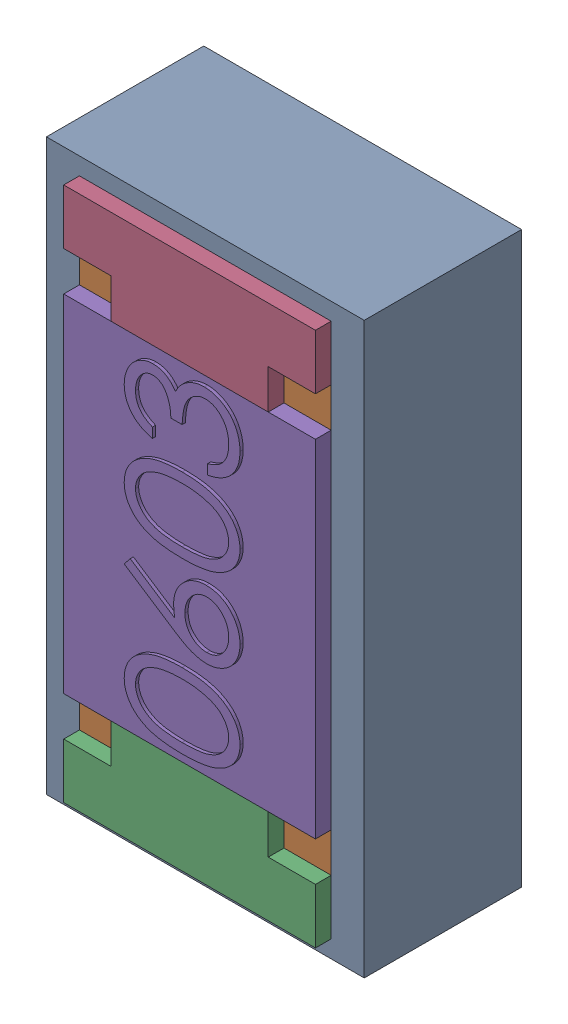
SolidWorks assembly SB5, configuration Default. Lengths in mm.
Overall size (1.01 1.81 0.56).
3 component instances, 2 part files, 0 mates.
Components (placement in the parent):
- 1088884704-1: 1088884704 [Default] at (13.8 21.425 0) size (1.01 1.81 0.5)
  - Extruded-0-1: Extruded-0 [Default] at origin size (1.01 1.81 0.5)
- R0603-1: R0603 [Default] at (13.7999 21.4251 0) x (0 1 0) z (1 0 0) size (1.7 0.56 0.8)
